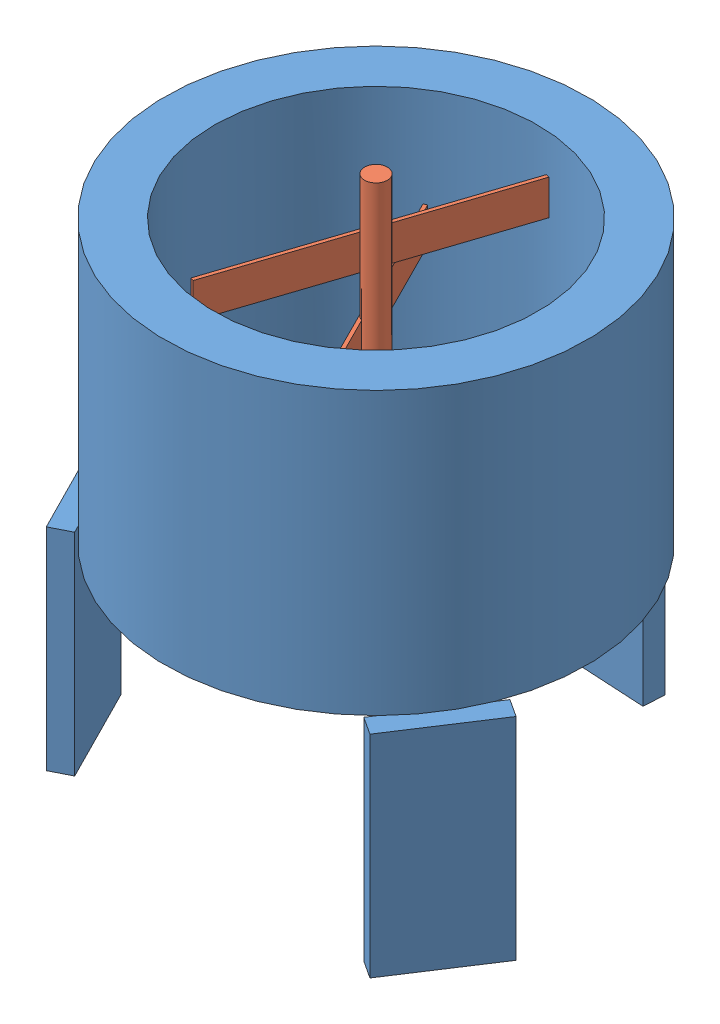
SolidWorks assembly Assemblage3, configuration Default. Lengths in mm.
Overall size (1739.07 1509.77 1746.16).
3 component instances, 3 part files, 4 mates.
Components (placement in the parent):
- CUVE500-1: CUVE500 [Défaut] at (761.9162 -536.8921 363.2241) x (0 1 0) z (0.837169 0 0.546944) size (1400 1271.24 1246.78)
- Bras multipales soudees evo1-1: Bras multipales soudees evo1 [Défaut] at (761.9162 453.1079 363.2241) x (-0.313587 0 0.949559) z (0.949559 0 0.313587) size (800 900.57 572.76)
- FOURREAU fixe fond-1: FOURREAU fixe fond [Défaut] at (761.9162 -366.8921 363.2241) x (-0.795223 0 -0.606317) z (-0.606317 0 0.795223) size (190 180 190)
Mates (geometry in assembly coordinates):
- Coaxiale1: concentric aligned: cylinder of CUVE500-1 through (761.9162 -562.1217 363.2241) axis (0 1 0) radius 27.5; cylinder of FOURREAU fixe fond-1 through (761.9162 -557.1217 363.2241) axis (0 1 0) radius 27.0528
- Coaxiale2: concentric aligned: cylinder of Bras multipales soudees evo1-1 through (761.9162 -346.8921 363.2241) axis (0 1 0) radius 32.5; cylinder of FOURREAU fixe fond-1 through (761.9162 -557.1217 363.2241) axis (0 1 0) radius 24.0528
- Coïncidente2: coincident anti-aligned: plane of CUVE500-1 through (597.8329 -507.1217 614.3748) normal (0 1 0); plane of FOURREAU fixe fond-1 through (761.9162 -507.1217 363.2241) normal (0 -1 0)
- Distance1: distance = 10 mm anti-aligned: plane of Bras multipales soudees evo1-1 through (761.9162 -356.8921 363.2241) normal (0 -1 0); plane of FOURREAU fixe fond-1 through (761.9162 -366.8921 363.2241) normal (0 1 0)
